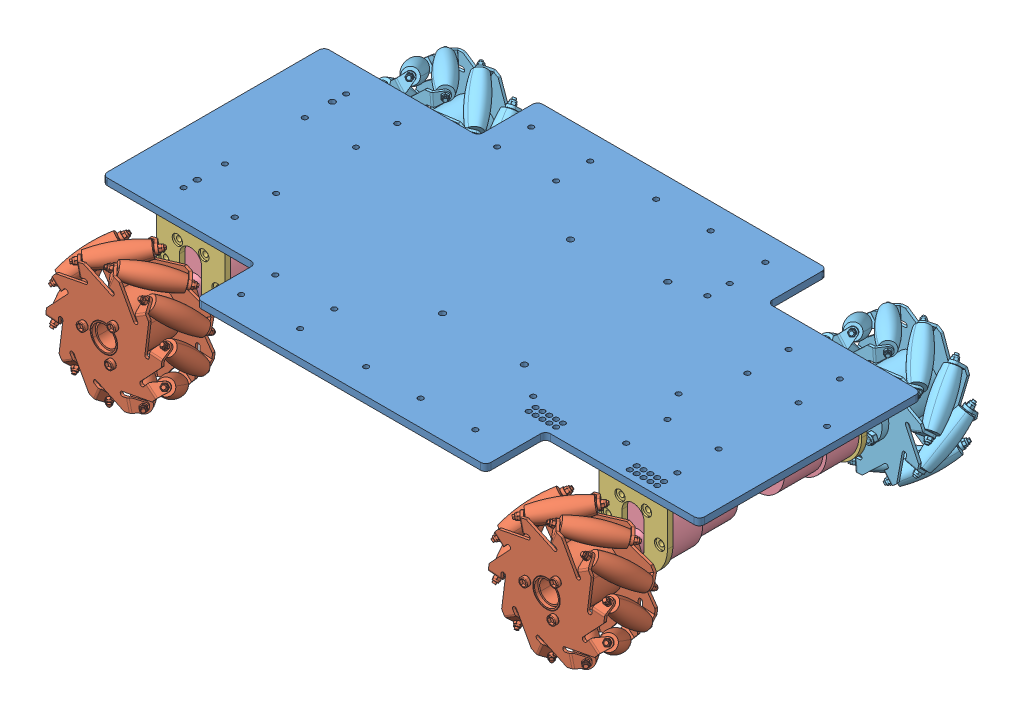
SolidWorks assembly 底板-麦轮装配体, configuration 默认. Lengths in mm.
Overall size (360.68 101.49 223.34).
13 component instances, 5 part files, 34 mates.
Components (placement in the parent):
- 车底板-1: 车底板 [默认] at (-4.9651 -34.2642 350) size (350 4 200)
- 75mecanumzuo-4: 75mecanumzuo [默认] at (-125.1754 -68.2642 364.1942) x (0.997346 -0.072807 0) z (-0.072807 -0.997346 0) size (77.38 50.5 75.94)
- 电机支架-7: 电机支架 [默认] at (-145.2754 -37.4642 343.8942) x (1 0 0) z (0 1 0) size (40.2 43 47)
- 新电机-1: 新电机 [默认] at (-125.1754 -61.2642 298.9942) x (-1 0 0) z (0 0 1) size (37 37 66.7)
- 新电机-2: 新电机 [默认] at (-124.8754 -61.2642 272.0527) x (1 0 0) z (0 0 -1) size (37 37 66.7)
- 电机支架-8: 电机支架 [默认] at (-104.7754 -37.4642 227.1527) x (-1 0 0) z (0 1 0) size (40.2 43 47)
- 75mecanumyou-3: 75mecanumyou [默认] at (-124.8754 -68.2642 206.8527) x (0.923728 0.383049 0) z (-0.383049 0.923728 0) size (77.38 50.5 77.78)
- 75mecanumzuo-6: 75mecanumzuo [默认] at (134.2366 -68.2642 364.1942) x (0.997346 -0.072807 0) z (-0.072807 -0.997346 0) size (77.38 50.5 75.94)
- 新电机-3: 新电机 [默认] at (134.2366 -61.2642 298.9942) x (-1 0 0) z (0 0 1) size (37 37 66.7)
- 电机支架-9: 电机支架 [默认] at (114.1366 -37.4642 343.8942) x (1 0 0) z (0 1 0) size (40.2 43 47)
- 新电机-4: 新电机 [默认] at (134.5366 -61.2642 272.0527) x (1 0 0) z (0 0 -1) size (37 37 66.7)
- 电机支架-10: 电机支架 [默认] at (154.6366 -37.4642 227.1527) x (-1 0 0) z (0 1 0) size (40.2 43 47)
- 75mecanumyou-4: 75mecanumyou [默认] at (134.5366 -68.2642 206.8527) x (0.923728 0.383049 0) z (-0.383049 0.923728 0) size (77.38 50.5 77.78)
Mates (geometry in assembly coordinates):
- 同心1: concentric anti-aligned: cylinder of 电机支架-7 through (-125.1754 -68.2642 300.8942) axis (0 0 1) radius 6.5; cylinder of 新电机-1 through (-125.1754 -68.2642 346.6942) axis (0 0 -1) radius 5.5
- 同心2: concentric aligned: cylinder of 电机支架-7 through (-132.9254 -74.6876 300.8942) axis (0 0 1) radius 1.5; cylinder of 新电机-1 through (-132.9254 -74.6876 338.6942) axis (0 0 1) radius 1.5
- 重合1: coincident anti-aligned: plane of 电机支架-7 through (-105.0754 -81.2642 340.6942) normal (0 0 -1); plane of 新电机-1 through (-125.1754 -61.2642 340.6942) normal (0 0 1)
- 同心4: concentric aligned: cylinder of 75mecanumzuo-4 through (-125.1754 -68.2642 346.6942) axis (0 0 -1) radius 3; cylinder of 新电机-1 through (-125.1754 -68.2642 362.1942) axis (0 0 -1) radius 3
- 重合2: coincident anti-aligned: plane of 75mecanumzuo-4 through (-125.1754 -68.2642 346.6942) normal (0 0 -1); plane of 新电机-1 through (-125.1754 -68.2642 346.6942) normal (0 0 1)
- 重合3: coincident anti-aligned: plane of 车底板-1 through (-4.9651 -34.2642 350) normal (0 -1 0); plane of 电机支架-7 through (-145.2754 -34.2642 343.8942) normal (0 1 0)
- 同心7: concentric anti-aligned: cylinder of 新电机-2 through (-124.8754 -68.2642 224.3527) axis (0 0 1) radius 5.5; cylinder of 电机支架-8 through (-124.8754 -68.2642 270.1527) axis (0 0 -1) radius 6.5
- 同心8: concentric aligned: cylinder of 新电机-2 through (-117.1254 -74.6876 232.3527) axis (0 0 -1) radius 1.5; cylinder of 电机支架-8 through (-117.1254 -74.6876 270.1527) axis (0 0 -1) radius 1.5
- 重合5: coincident anti-aligned: plane of 新电机-2 through (-124.8754 -61.2642 230.3527) normal (0 0 -1); plane of 电机支架-8 through (-144.9754 -81.2642 230.3527) normal (0 0 1)
- 同心10: concentric anti-aligned: cylinder of 新电机-2 through (-124.8754 -68.2642 208.8527) axis (0 0 1) radius 3; cylinder of 75mecanumyou-3 through (-124.8754 -68.2642 224.3527) axis (0 0 -1) radius 3
- 重合6: coincident anti-aligned: plane of 新电机-2 through (-124.8754 -68.2642 224.3527) normal (0 0 -1); plane of 75mecanumyou-3 through (-124.8754 -68.2642 224.3527) normal (0 0 1)
- 重合7: coincident anti-aligned: plane of 车底板-1 through (-4.9651 -34.2642 350) normal (0 -1 0); plane of 电机支架-8 through (-104.7754 -34.2642 227.1527) normal (0 1 0)
- 同心13: concentric anti-aligned: cylinder of 新电机-3 through (134.2366 -68.2642 346.6942) axis (0 0 -1) radius 5.5; cylinder of 电机支架-9 through (134.2366 -68.2642 300.8942) axis (0 0 1) radius 6.5
- 同心14: concentric aligned: cylinder of 新电机-3 through (126.4866 -74.6876 338.6942) axis (0 0 1) radius 1.5; cylinder of 电机支架-9 through (126.4866 -74.6876 300.8942) axis (0 0 1) radius 1.5
- 重合8: coincident anti-aligned: plane of 75mecanumzuo-6 through (134.2366 -68.2642 346.6942) normal (0 0 -1); plane of 新电机-3 through (134.2366 -68.2642 346.6942) normal (0 0 1)
- 同心15: concentric aligned: cylinder of 75mecanumzuo-6 through (134.2366 -68.2642 346.6942) axis (0 0 -1) radius 3; cylinder of 新电机-3 through (134.2366 -68.2642 362.1942) axis (0 0 -1) radius 3
- 重合9: coincident anti-aligned: plane of 新电机-3 through (134.2366 -61.2642 340.6942) normal (0 0 1); plane of 电机支架-9 through (154.3366 -81.2642 340.6942) normal (0 0 -1)
- 重合10: coincident anti-aligned: plane of 车底板-1 through (-4.9651 -34.2642 350) normal (0 -1 0); plane of 电机支架-9 through (114.1366 -34.2642 343.8942) normal (0 1 0)
- 同心18: concentric anti-aligned: cylinder of 新电机-4 through (134.5366 -68.2642 208.8527) axis (0 0 1) radius 3; cylinder of 75mecanumyou-4 through (134.5366 -68.2642 224.3527) axis (0 0 -1) radius 3
- 同心19: concentric aligned: cylinder of 新电机-4 through (142.2866 -74.6876 232.3527) axis (0 0 -1) radius 1.5; cylinder of 电机支架-10 through (142.2866 -74.6876 270.1527) axis (0 0 -1) radius 1.5
- 重合11: coincident anti-aligned: plane of 新电机-4 through (134.5366 -61.2642 230.3527) normal (0 0 -1); plane of 电机支架-10 through (114.4366 -81.2642 230.3527) normal (0 0 1)
- 同心20: concentric anti-aligned: cylinder of 新电机-4 through (134.5366 -68.2642 224.3527) axis (0 0 1) radius 5.5; cylinder of 电机支架-10 through (134.5366 -68.2642 270.1527) axis (0 0 -1) radius 6.5
- 重合12: coincident anti-aligned: plane of 新电机-4 through (134.5366 -68.2642 224.3527) normal (0 0 -1); plane of 75mecanumyou-4 through (134.5366 -68.2642 224.3527) normal (0 0 1)
- 重合13: coincident anti-aligned: plane of 车底板-1 through (-4.9651 -34.2642 350) normal (0 -1 0); plane of 电机支架-10 through (154.6366 -34.2642 227.1527) normal (0 1 0)
- 重合16: coincident: plane of 车底板-1 through (-4.9651 -34.2642 350) normal (0 -1 0); line of 电机支架-9 through (154.3366 -34.2642 343.8942) axis (0 0 -1)
- 重合17: coincident: plane of 车底板-1 through (-4.9651 -34.2642 350) normal (0 -1 0); line of 电机支架-10 through (154.6366 -34.2642 227.1527) axis (0 0 1)
- 同心23: concentric aligned: cylinder of 车底板-1 through (-140.0254 -30.2642 333.1442) axis (0 -1 0) radius 1.5; cylinder of 电机支架-7 through (-140.0254 -34.2642 333.1442) axis (0 -1 0) radius 1.75
- 同心24: concentric aligned: cylinder of 车底板-1 through (-110.0254 -30.2642 333.1442) axis (0 -1 0) radius 1.5; cylinder of 电机支架-7 through (-110.0254 -34.2642 333.1442) axis (0 -1 0) radius 1.75
- 同心25: concentric aligned: cylinder of 车底板-1 through (-110.0254 -30.2642 237.9027) axis (0 -1 0) radius 1.5; cylinder of 电机支架-8 through (-110.0254 -34.2642 237.9027) axis (0 -1 0) radius 1.75
- 同心26: concentric aligned: cylinder of 车底板-1 through (-140.0254 -30.2642 237.9027) axis (0 -1 0) radius 1.5; cylinder of 电机支架-8 through (-140.0254 -34.2642 237.9027) axis (0 -1 0) radius 1.75
- 同心27: concentric aligned: cylinder of 车底板-1 through (149.3866 -30.2642 237.9027) axis (0 -1 0) radius 1.5; cylinder of 电机支架-10 through (149.3866 -34.2642 237.9027) axis (0 -1 0) radius 1.75
- 同心28: concentric aligned: cylinder of 车底板-1 through (119.3866 -30.2642 237.9027) axis (0 -1 0) radius 1.5; cylinder of 电机支架-10 through (119.3866 -34.2642 237.9027) axis (0 -1 0) radius 1.75
- 同心29: concentric aligned: cylinder of 车底板-1 through (119.3866 -30.2642 333.1442) axis (0 -1 0) radius 1.5; cylinder of 电机支架-9 through (119.3866 -34.2642 333.1442) axis (0 -1 0) radius 1.75
- 同心30: concentric aligned: cylinder of 车底板-1 through (149.3866 -30.2642 333.1442) axis (0 -1 0) radius 1.5; cylinder of 电机支架-9 through (149.3866 -34.2642 333.1442) axis (0 -1 0) radius 1.75
